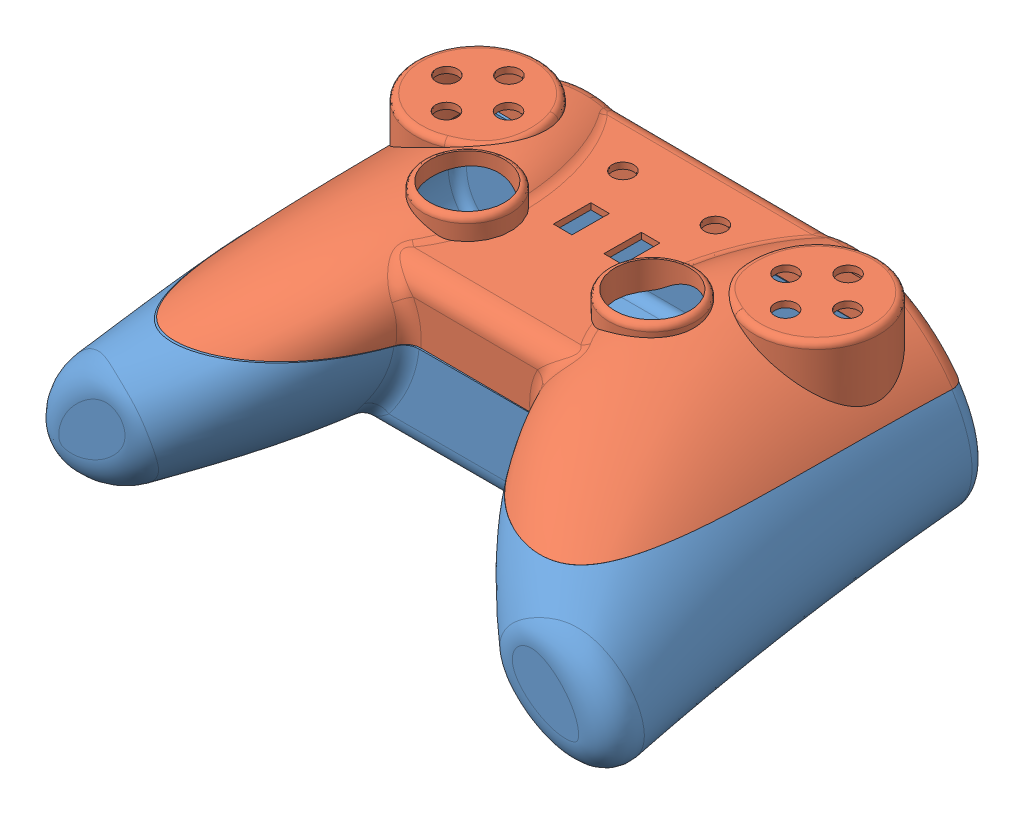
SolidWorks assembly Assem1, configuration Default. Lengths in mm.
Overall size (190.44 72.84 131.42).
2 component instances, 2 part files, 2 mates.
Components (placement in the parent):
- Bottom-1: Bottom [Default] at (-23.1656 6.0224 0.2496) size (190.44 71.22 130.43)
- Top-1: Top [Default] at (-22.8658 6.0224 -0.1473) x (0.999978 0 0.006632) z (-0.006632 0 0.999978) size (177.43 44.61 122.5)
Mates (geometry in assembly coordinates):
- Concentric1: concentric aligned: circle of Bottom-1; circle of Top-1
- Coincident1: coincident anti-aligned: plane of Bottom-1 through (126.8344 6.0224 -50.0797) normal (0 1 0); plane of Top-1 through (127.4646 6.0224 -49.4807) normal (0 -1 0)
